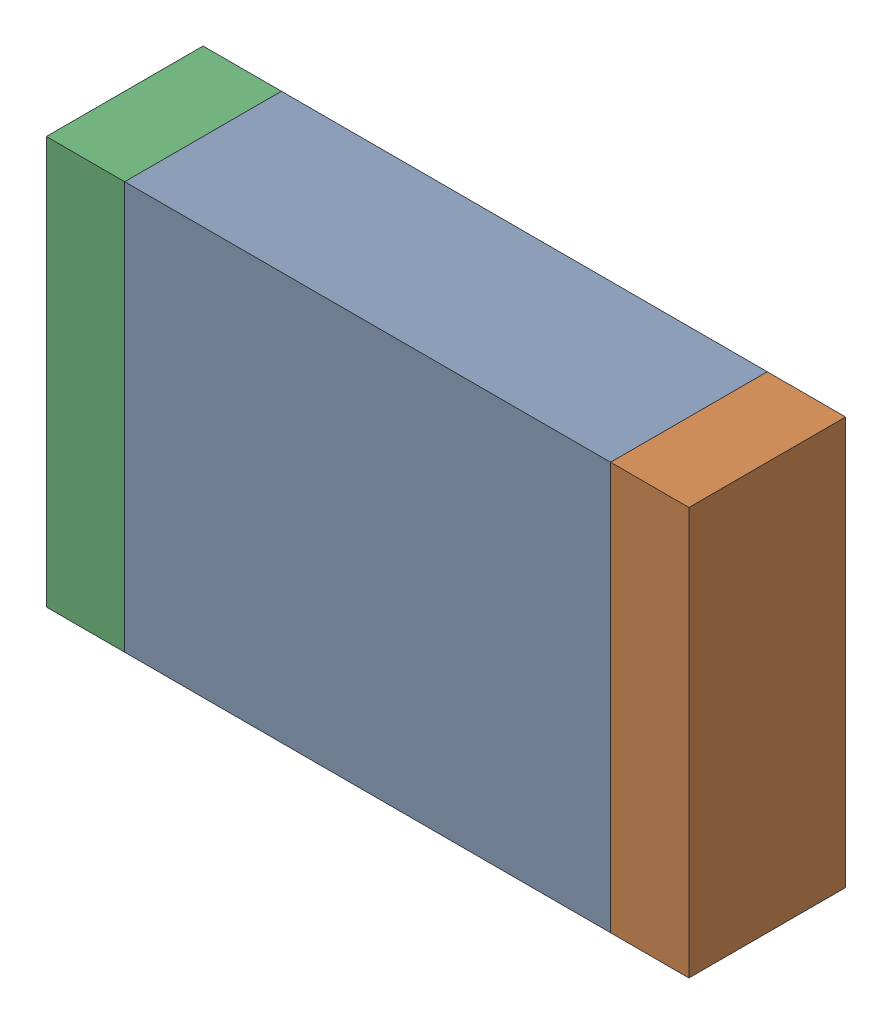
SolidWorks assembly C55, configuration Default. Lengths in mm.
Overall size (2.05 1.3 0.5).
6 component instances, 2 part files, 0 mates.
Components (placement in the parent):
- 836756464-1: 836756464 [Default] at (124.875 47.05 0) size (1.55 1.3 0.5)
  - Extruded_42-1: Extruded_42 [Default] at origin size (1.55 1.3 0.5)
- 836756336-1: 836756336 [Default] at (125.775 47.05 0) size (0.25 1.3 0.5)
  - Extruded_41-1: Extruded_41 [Default] at origin size (0.25 1.3 0.5)
- 836756336-2: 836756336 [Default] at (123.975 47.05 0) size (0.25 1.3 0.5)
  - Extruded_41-1: Extruded_41 [Default] at origin size (0.25 1.3 0.5)
